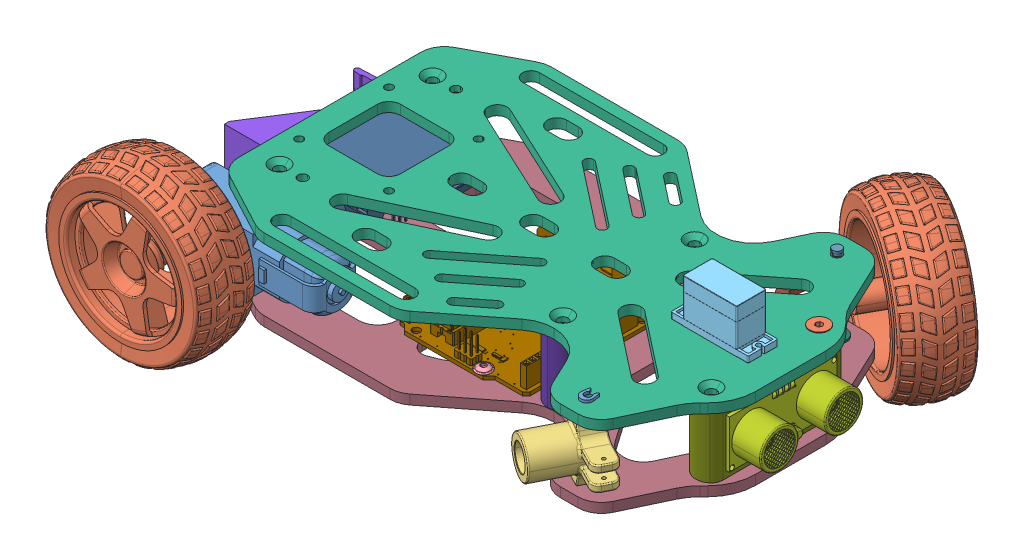
SolidWorks assembly Wheel, configuration Default. Lengths in mm.
Overall size (79.48 74.2 61.95).
74 component instances, 24 part files, 0 mates.
Components (placement in the parent):
- Assieme3^Macchina_2_sterzante.STEP-1: Assieme3^Macchina_2_sterzante.STEP [Default] at origin size (88.7 69.02 57.8) (hidden)
  - Motor_Gear_Box_Standard.STEP-1: Motor_Gear_Box_Standard.STEP [Default] at (-91.71 -1.7 39) x (1 0 0) z (0 0 -1) size (70.5 22.6 37.6)
  - Wheel D65x25___ _________.STEP-1: Wheel D65x25___ _________.STEP [Default] at (-80.41 -13 87.1) x (0 -1 0) z (0 0 1) size (69.02 69.02 30)
- Assieme3^Macchina_2_sterzante.STEP-2: Assieme3^Macchina_2_sterzante.STEP [Default] at (0 -26 0) x (1 0 0) z (0 0 -1) size (88.7 69.02 57.8) (hidden)
  - Motor_Gear_Box_Standard.STEP-1: Motor_Gear_Box_Standard.STEP [Default] at (-91.71 -1.7 39) x (1 0 0) z (0 0 -1) size (70.5 22.6 37.6)
  - Wheel D65x25___ _________.STEP-1: Wheel D65x25___ _________.STEP [Default] at (-80.41 -13 87.1) x (0 -1 0) z (0 0 1) size (69.02 69.02 30)
- Ruota_ant_sterzante.STEP-1: Ruota_ant_sterzante.STEP [Default] at (70.3229 -13 70.9748) x (-0.890837 0 -0.454323) z (-0.454323 0 0.890837) size (74.19 74.2 40.2) (hidden)
  - mozzo1.STEP-1: mozzo1.STEP [Default] at origin size (26 24 27) (hidden)
  - Semiasse1.STEP-1: Semiasse1.STEP [Default] at (0 0 -7) x (0.996952 -0.078016 0) z (0 0 1) size (12 12 12) (hidden)
  - Wheel D65x25___ _________.STEP-1: Wheel D65x25___ _________.STEP [Default] at (0 0 13.2) x (0.996952 -0.078016 0) z (0 0 1) size (69.02 69.02 30)
- Ruota_ant_sterzante.STEP-2: Ruota_ant_sterzante.STEP [Default] at (90.2328 -13 -70.681) x (0.877042 0 0.480414) z (0.480414 0 -0.877042) size (74.19 74.2 40.2)
  - mozzo1.STEP-1: mozzo1.STEP [Default] at origin size (26 24 27) (hidden)
  - Semiasse1.STEP-1: Semiasse1.STEP [Default] at (0 0 -7) x (0.996952 -0.078016 0) z (0 0 1) size (12 12 12) (hidden)
  - Wheel D65x25___ _________.STEP-1: Wheel D65x25___ _________.STEP [Default] at (0 0 13.2) x (0.996952 -0.078016 0) z (0 0 1) size (69.02 69.02 30)
- microservoAssembly.STEP-1: microservoAssembly.STEP [Default] at (77.0906 25.5655 26.0266) x (1 0 0) z (0 0 -1) size (32.3 29.8 12.41) (hidden)
  - microservoSG90.STEP-1: microservoSG90.STEP [Default] at (7.8094 3.3655 26.0766) size (32.3 29.8 12.41)
- Chassis2.STEP-1: Chassis2.STEP [Default] at origin size (192.71 4 120) (hidden)
- Ultrasonic HCSR04.STEP-1: Ultrasonic HCSR04.STEP [Default] at (108 -90.6627 49.1494) x (0 0 1) z (1 0 0) size (45 24.45 19.2) (hidden)
- 9V Battery Holder.STEP-1: 9V Battery Holder.STEP [Default] at (-77 2 27) x (0 -1 0) z (0 0 -1) size (30 20 54) (hidden)
- arduinoUno_Detailed.STEP-1: arduinoUno_Detailed.STEP [Default] at (10.5214 -26 2.03) x (0 0 1) z (-1 0 0) size (75.4 14.5 53.4) (hidden)
- L298N Motor Driver.STEP-1: L298N Motor Driver.STEP [Default] at (-55.25 0 0) x (0 0 -1) z (-1 0 0) size (43.5 26 43.5) (hidden)
- barra_sterzo3.STEP-1: barra_sterzo3.STEP [Default] at (89.0969 -13 -12.0753) x (0.904276 0 -0.426947) z (0.426947 0 0.904276) size (11.62 8.3 56.12) (hidden)
- microservoArm_A2.STEP-1: microservoArm_A2.STEP [Default] at (79.8 -9.1 -0.05) x (0.611636 0 -0.791139) z (0.791139 0 0.611636) size (34.4 3.9 7) (hidden)
- barra_sterzo3.STEP-2: barra_sterzo3.STEP [Default] at (70.5031 -13 11.9753) x (-0.898686 0 0.438592) z (-0.438592 0 -0.898686) size (11.62 8.3 56.12) (hidden)
- Copri_Chassis2.STEP-1: Copri_Chassis2.STEP [Default] at (0 -30 0) size (192.71 4 120) (hidden)
- perno_sterzo.STEP-1: perno_sterzo.STEP [Default] at (80 -1 -52) size (8 38.6 8) (hidden)
- spessore_sterzo.STEP-1: spessore_sterzo.STEP [Default] at (80 -25.8 -52) size (8 0.8 8) (hidden)
- mascherina.STEP-1: mascherina.STEP [Default] at (102 -26 22.5) x (0 0 -1) z (1 0 0) size (58 26 12.5) (hidden)
- colonnetta.STEP-1: colonnetta.STEP [Default] at (45 -26 27.5) size (13 26 13) (hidden)
- colonnetta.STEP-2: colonnetta.STEP [Default] at (45 -26 -27.5) size (13 26 13) (hidden)
- supporto_motore.STEP-1: supporto_motore.STEP [Default] at (-69 -26 -32) x (0 0 1) z (-1 0 0) size (14 30 21) (hidden)
- supporto_motore.STEP-2: supporto_motore.STEP [Default] at (-69 -26 32) x (0 0 1) z (-1 0 0) size (14 30 21) (hidden)
- perno_sterzo.STEP-2: perno_sterzo.STEP [Default] at (80 -1 52) size (8 38.6 8) (hidden)
- spessore_sterzo.STEP-2: spessore_sterzo.STEP [Default] at (80 -26 52) size (8 0.8 8) (hidden)
- seeger3.STEP-1: seeger3.STEP [Default] at (80 4.1 52) size (5 1.1 5.94) (hidden)
- seeger3.STEP-2: seeger3.STEP [Default] at (80 5.3 -52) x (-0.837169 0 -0.546944) z (-0.546944 0 0.837169) size (5 1.1 5.94) (hidden)
- seeger3.STEP-3: seeger3.STEP [Default] at (80 -30.1 52) x (-0.837169 0 -0.546944) z (-0.546944 0 0.837169) size (5 1.1 5.94) (hidden)
- seeger3.STEP-4: seeger3.STEP [Default] at (80 -30.1 -52) x (-0.837169 0 -0.546944) z (-0.546944 0 0.837169) size (5 1.1 5.94) (hidden)
- DIN7991_M4x35_ISO 7991 M04 x  20.STEP-1: DIN7991_M4x35_ISO 7991 M04 x  20.STEP [Default] at (102 4.3 -22.5) x (0 -1 0) z (0.040394 0 0.999184) size (37.3 8 8) (hidden)
- DIN7991_M4x35_ISO 7991 M04 x  20.STEP-2: DIN7991_M4x35_ISO 7991 M04 x  20.STEP [Default] at (102 4.3 22.5) x (0 -1 0) z (-0.992579 0 -0.121599) size (37.3 8 8) (hidden)
- M4 Nut.STEP-1: M4 Nut.STEP [Default] at (102 -30 -22.5) x (1 0 0) z (0 -1 0) size (8.1 8.09 3.22) (hidden)
- DIN7991_M4x35_ISO 7991 M04 x  20.STEP-3: DIN7991_M4x35_ISO 7991 M04 x  20.STEP [Default] at (45 4.3 -27.5) x (0 -1 0) z (-0.992579 0 -0.121599) size (37.3 8 8) (hidden)
- DIN7991_M4x35_ISO 7991 M04 x  20.STEP-4: DIN7991_M4x35_ISO 7991 M04 x  20.STEP [Default] at (-69 4.3 -32) x (0 -1 0) z (-0.992579 0 -0.121599) size (37.3 8 8) (hidden)
- DIN7991_M4x35_ISO 7991 M04 x  20.STEP-5: DIN7991_M4x35_ISO 7991 M04 x  20.STEP [Default] at (-69 4.3 32) x (0 -1 0) z (-0.992579 0 -0.121599) size (37.3 8 8) (hidden)
- DIN7991_M4x35_ISO 7991 M04 x  20.STEP-6: DIN7991_M4x35_ISO 7991 M04 x  20.STEP [Default] at (45 4.3 27.5) x (0 -1 0) z (-0.992579 0 -0.121599) size (37.3 8 8) (hidden)
- M4 Nut.STEP-2: M4 Nut.STEP [Default] at (102 -30 22.5) x (1 0 0) z (0 -1 0) size (8.1 8.09 3.22) (hidden)
- M4 Nut.STEP-3: M4 Nut.STEP [Default] at (-69 -30 -32) x (0.920165 0 0.391532) z (0 -1 0) size (8.1 8.09 3.22) (hidden)
- M4 Nut.STEP-4: M4 Nut.STEP [Default] at (45 -30 27.5) x (1 0 0.000614) z (0 -1 0) size (8.1 8.09 3.22) (hidden)
- M4 Nut.STEP-5: M4 Nut.STEP [Default] at (45 -30 -27.5) x (0.998478 0 0.055145) z (0 -1 0) size (8.1 8.09 3.22) (hidden)
- M4 Nut.STEP-6: M4 Nut.STEP [Default] at (-69 -30 32) x (0.949732 0 0.313063) z (0 -1 0) size (8.1 8.09 3.22) (hidden)
- DIN_EN_ISO_7380_M3x8.ipt.STEP-1: DIN_EN_ISO_7380_M3x8.ipt.STEP [Default] at (19.3514 -24.5 35.06) x (-0.613574 0 0.789637) z (0 1 0) size (6.44 6.44 9.5) (hidden)
- DIN_EN_ISO_7380_M3x8.ipt.STEP-2: DIN_EN_ISO_7380_M3x8.ipt.STEP [Default] at (-36.5 4 18.75) x (0.99735 0 0.072756) z (0 1 0) size (6.44 6.44 9.5) (hidden)
- DIN_EN_ISO_7380_M3x8.ipt.STEP-3: DIN_EN_ISO_7380_M3x8.ipt.STEP [Default] at (-8.8186 -24.5 35.06) x (0.998471 0 -0.055271) z (0 1 0) size (6.44 6.44 9.5) (hidden)
- DIN_EN_ISO_7380_M3x8.ipt.STEP-4: DIN_EN_ISO_7380_M3x8.ipt.STEP [Default] at (-74 4 -18.75) x (0.999981 0 -0.00624) z (0 1 0) size (6.44 6.44 9.5) (hidden)
- DIN_EN_ISO_7380_M3x8.ipt.STEP-5: DIN_EN_ISO_7380_M3x8.ipt.STEP [Default] at (-36.5 4 -18.75) x (0.998879 0 0.047332) z (0 1 0) size (6.44 6.44 9.5) (hidden)
- DIN_EN_ISO_7380_M3x8.ipt.STEP-6: DIN_EN_ISO_7380_M3x8.ipt.STEP [Default] at (-74 4 18.75) x (0.933529 0 0.358501) z (0 1 0) size (6.44 6.44 9.5) (hidden)
- M3 Nut.STEP-1: M3 Nut.STEP [Default] at (-13.6386 -30 -17) x (1 0 0) z (0 -1 0) size (6.36 6.36 2.41) (hidden)
- M3 Nut.STEP-2: M3 Nut.STEP [Default] at (-8.8186 -32.4 35.06) x (-0.690778 0 0.723067) z (0 1 0) size (6.36 6.36 2.41) (hidden)
- M3 Nut.STEP-3: M3 Nut.STEP [Default] at (34.6814 -30 -15.75) x (1 0 0) z (0 -1 0) size (6.36 6.36 2.41) (hidden)
- M3 Nut.STEP-4: M3 Nut.STEP [Default] at (19.3514 -32.4 35.06) x (1 0 0) z (0 1 0) size (6.36 6.36 2.41) (hidden)
- DIN_EN_ISO_7380_M3x8.ipt.STEP-7: DIN_EN_ISO_7380_M3x8.ipt.STEP [Default] at (-13.6386 -24.5 -17) x (-0.613574 0 0.789637) z (0 1 0) size (6.44 6.44 9.5) (hidden)
- DIN_EN_ISO_7380_M3x8.ipt.STEP-8: DIN_EN_ISO_7380_M3x8.ipt.STEP [Default] at (34.6814 -24.5 -15.75) x (0.904734 0 -0.425977) z (0 1 0) size (6.44 6.44 9.5) (hidden)
- M3 Nut.STEP-5: M3 Nut.STEP [Default] at (-74 -1.5 -18.75) x (0.964342 0 -0.264661) z (0 -1 0) size (6.36 6.36 2.41) (hidden)
- M3 Nut.STEP-6: M3 Nut.STEP [Default] at (-36.5 -1.5 -18.75) x (1 0 0) z (0 -1 0) size (6.36 6.36 2.41) (hidden)
- M3 Nut.STEP-7: M3 Nut.STEP [Default] at (-74 -1.5 18.75) x (0.994576 0 -0.104011) z (0 -1 0) size (6.36 6.36 2.41) (hidden)
- M3 Nut.STEP-8: M3 Nut.STEP [Default] at (-36.5 -1.5 18.75) x (1 0 0) z (0 -1 0) size (6.36 6.36 2.41) (hidden)
- ISO 7380_M3x35_ISO 7380 - M3 x 10.STEP-1: ISO 7380_M3x35_ISO 7380 - M3 x 10.STEP [Default] at (-59.91 -4 -58.85) x (0 0 1) z (-0.999411 0.034306 0) size (36.65 5.7 5.7) (hidden)
- ISO 7380_M3x35_ISO 7380 - M3 x 10.STEP-2: ISO 7380_M3x35_ISO 7380 - M3 x 10.STEP [Default] at (-59.91 -22 58.85) x (0 0 -1) z (0.958742 0.284277 0) size (36.65 5.7 5.7) (hidden)
- ISO 7380_M3x35_ISO 7380 - M3 x 10.STEP-3: ISO 7380_M3x35_ISO 7380 - M3 x 10.STEP [Default] at (-59.91 -4 58.85) x (0 0 -1) z (0.983256 0.182229 0) size (36.65 5.7 5.7) (hidden)
- ISO 7380_M3x35_ISO 7380 - M3 x 10.STEP-4: ISO 7380_M3x35_ISO 7380 - M3 x 10.STEP [Default] at (-59.91 -22 -58.85) x (0 0 1) z (-0.742875 0.66943 0) size (36.65 5.7 5.7) (hidden)
- M3 Nut.STEP-9: M3 Nut.STEP [Default] at (-59.91 -22 25) x (1 0 0) z (0 0 -1) size (6.36 6.36 2.41) (hidden)
- M3 Nut.STEP-10: M3 Nut.STEP [Default] at (-59.91 -22 -25) x (0.995162 0.098253 0) z (0 0 1) size (6.36 6.36 2.41) (hidden)
- M3 Nut.STEP-11: M3 Nut.STEP [Default] at (-59.91 -4 25) x (1 0 0) z (0 0 -1) size (6.36 6.36 2.41) (hidden)
- M3 Nut.STEP-12: M3 Nut.STEP [Default] at (-59.91 -4 -25) x (0.94863 -0.316387 0) z (0 0 1) size (6.36 6.36 2.41) (hidden)
